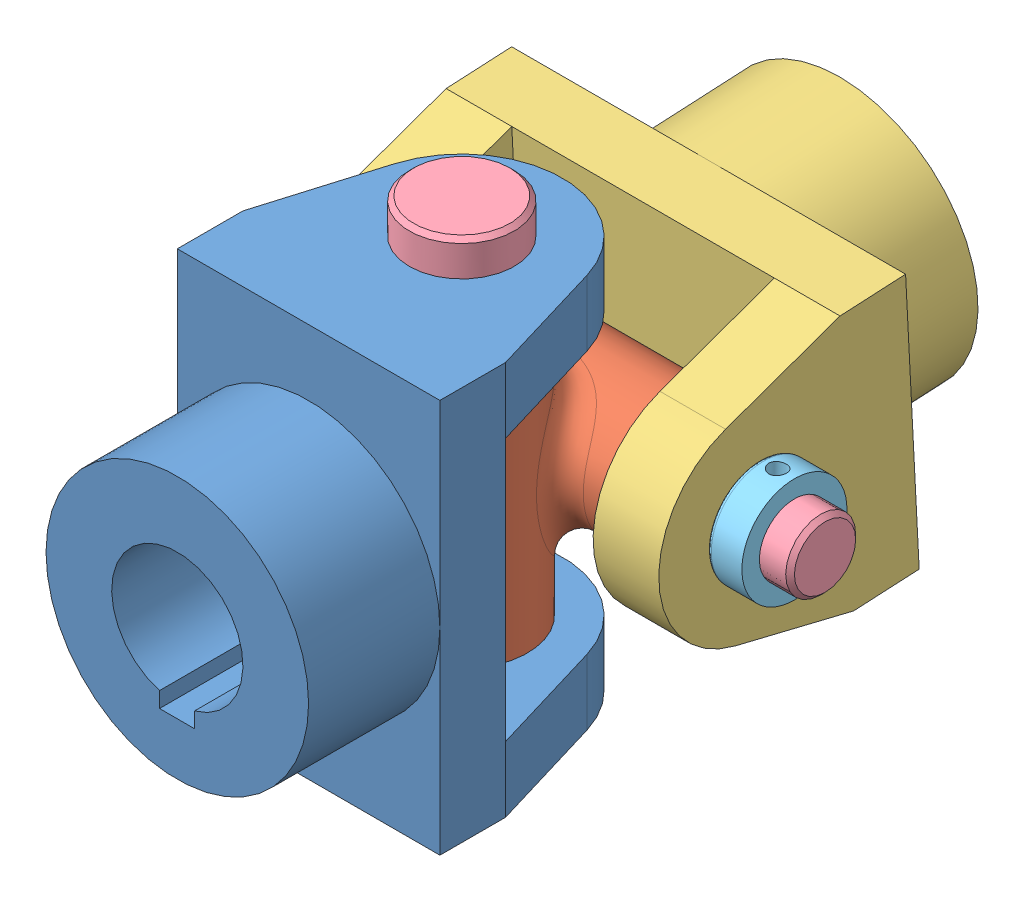
SolidWorks assembly Assem2, configuration Default. Lengths in mm.
Overall size (113 113 154.46).
7 component instances, 5 part files, 12 mates.
Components (placement in the parent):
- 1. Driving yoke-1: 1. Driving yoke [Default] at (48.2388 50.6574 57.8479) size (60 90 88)
- 2. Cross Bearing-1: 2. Cross Bearing [Default] at (48.2388 50.6574 37.8479) size (60 60 53)
- 6. Driven yoke-1: 6. Driven yoke [Default] at (48.2388 51.692 -5.1253) x (0 -0.998661 -0.05173) z (0 0.05173 -0.998661) size (60 90 88)
- 3. Bolt-1: 3. Bolt [Default] at (-4.7612 50.6574 14.8479) x (1 0 0) z (0 0.014647 0.999893) size (113 24 24)
- 3. Bolt-2: 3. Bolt [Default] at (48.2388 103.6574 37.8479) x (0 -1 0) z (0.003864 0 0.999993) size (113 24 24)
- 4. Bush-1: 4. Bush [Default] at (48.2388 -2.3426 37.8479) x (0.999993 0 -0.003864) z (0.003864 0 0.999993) size (24 8 24)
- 4. Bush-2: 4. Bush [Default] at (101.2388 50.6574 14.8479) x (0 0.999893 -0.014647) z (0 0.014647 0.999893) size (24 8 24)
Mates (geometry in assembly coordinates):
- Coincident3: coincident aligned: circle of 1. Driving yoke-1; circle of 2. Cross Bearing-1
- Coincident4: coincident anti-aligned: circle of 2. Cross Bearing-1; circle of 6. Driven yoke-1
- Concentric1: concentric anti-aligned: cylinder of 6. Driven yoke-1 through (78.2388 50.6574 14.8479) axis (1 0 0) radius 8; cylinder of 3. Bolt-1 through (108.2388 50.6574 14.8479) axis (-1 0 0) radius 8
- Coincident5: coincident anti-aligned: plane of 6. Driven yoke-1 through (3.2388 82.4278 -18.5534) normal (-1 0 0); plane of 3. Bolt-1 through (3.2388 50.6574 14.8479) normal (1 0 0)
- Concentric3: concentric anti-aligned: circle of 1. Driving yoke-1; circle of 3. Bolt-2
- Coincident6: coincident anti-aligned: plane of 1. Driving yoke-1 through (18.2388 95.6574 72.8479) normal (0 1 0); plane of 3. Bolt-2 through (48.2388 95.6574 37.8479) normal (0 -1 0)
- Concentric5: concentric anti-aligned: cylinder of 3. Bolt-1 through (108.2388 50.6574 14.8479) axis (-1 0 0) radius 8; cylinder of 4. Bush-2 through (93.2388 50.6574 14.8479) axis (1 0 0) radius 8
- Coincident7: coincident anti-aligned: plane of 6. Driven yoke-1 through (93.2388 82.4278 -18.5534) normal (1 0 0); circle of 4. Bush-2
- Concentric6: concentric aligned: cylinder of 3. Bolt-1 through (97.2388 -1.8369 15.6169) axis (0 0.999893 -0.014647) radius 2; cylinder of 4. Bush-2 through (97.2388 26.66 15.1994) axis (0 0.999893 -0.014647) radius 2
- Concentric7: concentric aligned: circle of 3. Bolt-2; circle of 4. Bush-1
- Coincident8: coincident anti-aligned: plane of 1. Driving yoke-1 through (18.2388 5.6574 72.8479) normal (0 -1 0); circle of 4. Bush-1
- Concentric8: concentric aligned: cylinder of 3. Bolt-2 through (-4.2608 1.6574 38.0507) axis (0.999993 0 -0.003864) radius 2; cylinder of 4. Bush-1 through (24.239 1.6574 37.9406) axis (0.999993 0 -0.003864) radius 2
